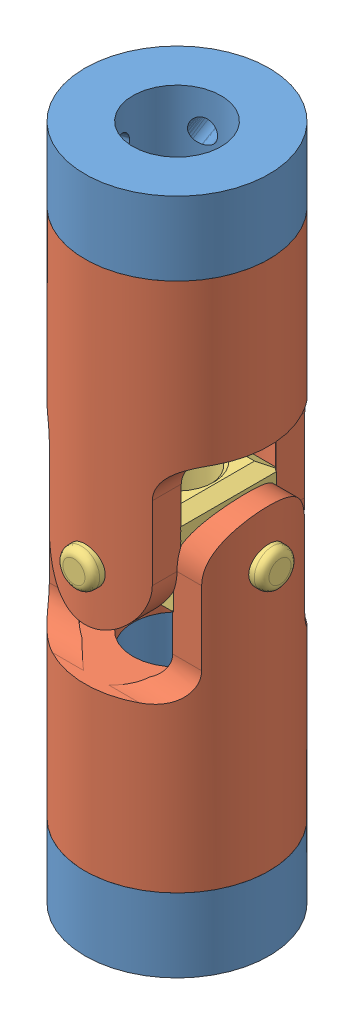
SolidWorks assembly acopolamento, configuration Default. Lengths in mm.
Overall size (16 46 16).
5 component instances, 3 part files, 8 mates.
Components (placement in the parent):
- encaixe-1: encaixe [Default] at origin size (12.5 15 12.5)
- capa-1: capa [Default] at (0 2.5 0) x (1 0 0.000214) z (-0.000214 0 1) size (12.5 21.5 12.5)
- elo-1: elo [Default] at (0 23.5 0) x (1 0 0.000214) z (0.000214 0 -1) size (14 6 14)
- capa-2: capa [Default] at (0 38.5 0) x (-0.000214 0 1) z (1 0 0.000214) size (12.5 21.5 12.5)
- encaixe-2: encaixe [Default] at (0 41 0) x (0.339862 0 0.940475) z (0.940475 0 -0.339862) size (12.5 15 12.5)
Mates (geometry in assembly coordinates):
- Concentric1: concentric aligned: cylinder of encaixe-1; cylinder of capa-1
- Coincident1: coincident anti-aligned: plane of encaixe-1 through (0 2.5 0) normal (0 1 0); plane of capa-1 through (0 2.5 0) normal (0 -1 0)
- Concentric2: concentric anti-aligned: cylinder of capa-1; cylinder of elo-1
- Coincident2: coincident aligned: plane of capa-1 through (0 2.5 0) normal (1 0 0.000214); plane of elo-1 through (0 23.5 0) normal (1 0 0.000214)
- Concentric3: concentric anti-aligned: cylinder of elo-1; cylinder of capa-2
- Coincident3: coincident anti-aligned: plane of elo-1 through (0 23.5 0) normal (0.000214 0 -1); plane of capa-2 through (0 38.5 0) normal (-0.000214 0 1)
- Concentric4: concentric aligned: cylinder of capa-2; cylinder of encaixe-2
- Coincident4: coincident anti-aligned: plane of capa-2 through (0 38.5 0) normal (0 1 0); plane of encaixe-2 through (0 38.5 0) normal (0 -1 0)
